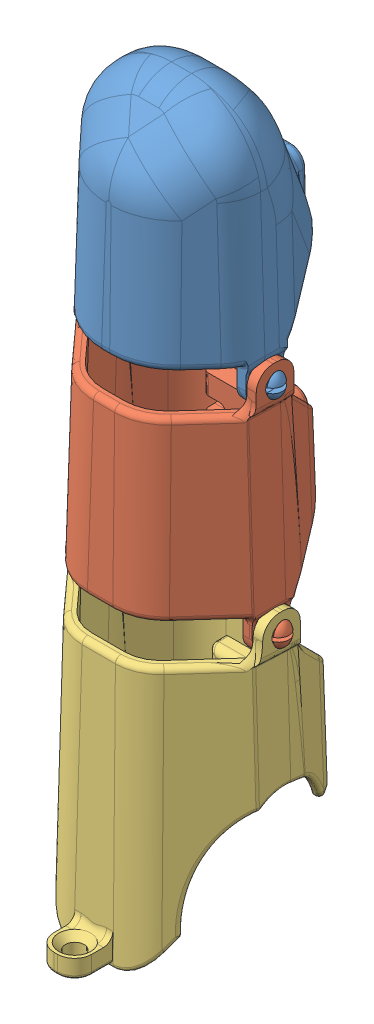
SolidWorks assembly finger_ring, configuration Default. Lengths in mm.
Overall size (28.25 98.11 30.22).
3 component instances, 3 part files, 6 mates.
Components (placement in the parent):
- ring_distal-1: ring_distal [Default] at (-15.3715 -8.7619 -7.8557) x (1 0 0) z (0 0.001844 0.999998) size (26.33 33.72 22.56)
- ring_middle-1: ring_middle [Default] at (-15.4138 -8.7619 -7.8557) x (1 0 0) z (0 0.001844 0.999998) size (28.25 33.66 23.59)
- ring_proximal-1: ring_proximal [Default] at (-15.4493 -10.7743 -7.8979) size (27.27 40.88 30.22)
Mates (geometry in assembly coordinates):
- Concentric2: concentric anti-aligned: circle of ring_middle-1; circle of ring_proximal-1
- Distance2: distance = 0.127 mm anti-aligned: plane of ring_middle-1 through (8.2505 11.5986 14.0529) normal (1 0 0); plane of ring_proximal-1 through (8.3775 16.6577 14.9445) normal (-1 0 0)
- Concentric3: concentric anti-aligned: circle of ring_distal-1; circle of ring_middle-1
- Distance3: distance = 0.127 mm anti-aligned: plane of ring_middle-1 through (7.4673 45.2534 13.9395) normal (-1 0 0); plane of ring_distal-1 through (7.3403 40.171 12.6027) normal (1 0 0)
- Parallel3: parallel aligned: plane of ring_distal-1 through (9.7533 43.0125 3.9524) normal (0 -0.999998 0.001844); plane of ring_middle-1 through (10.6635 14.3741 4.0052) normal (0 -0.999998 0.001844)
- Parallel4: parallel aligned: plane of ? through (1.3547 24.723 -9.5743) normal (0 -0.999785 -0.02075); plane of ring_proximal-1 through (1.3909 -7.6404 -10.2464) normal (0 -0.999785 -0.02075)
